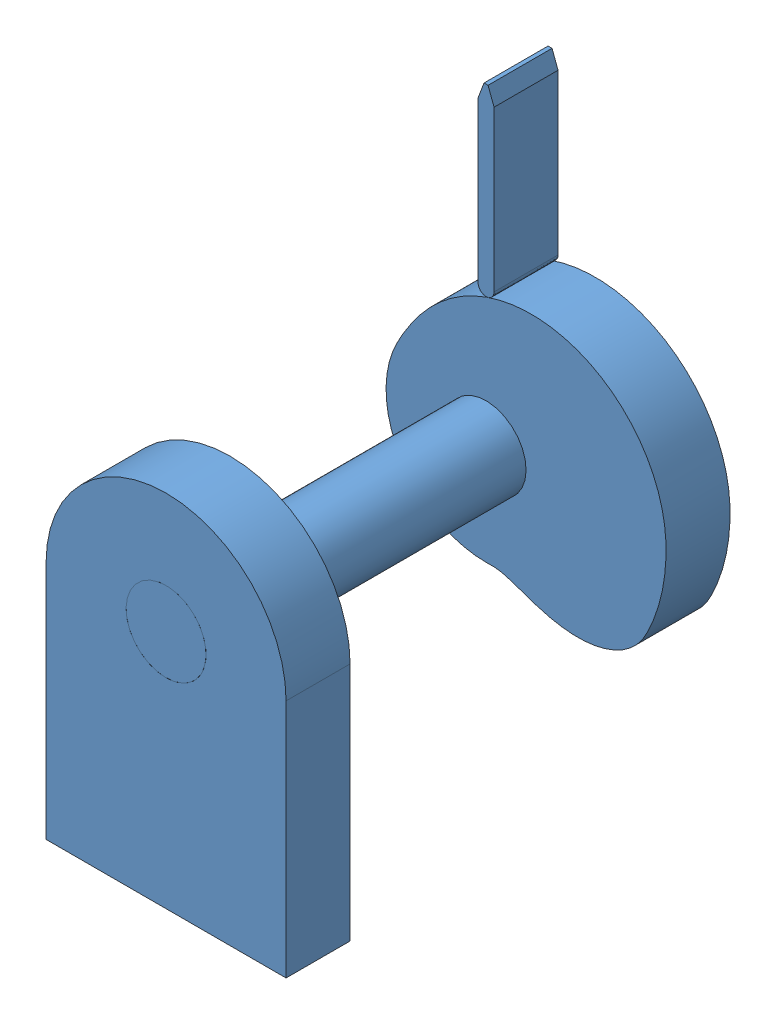
SolidWorks assembly Ensamble_Leva_2, configuration Default. Lengths in mm.
Overall size (515.65 692.74 480).
4 component instances, 1 part files, 7 mates.
Components (placement in the parent):
- Leva_2-1: Leva_2 [Soporte] at (155.9619 263.6656 402.9067) size (375 450 80)
- Leva_2-2: Leva_2 [Eje] at (155.9619 263.6656 42.9067) x (-0.887814 0.460203 0) z (0 0 1) size (350 322.5 480)
- Leva_2-3: Leva_2 [Leva] at (155.9619 263.6656 2.9067) x (-0.887814 0.460203 0) z (0 0 1) size (350 322.5 80)
- Leva_2-5: Leva_2 [Seguidor] at (155.9619 436.4083 -37.0933) size (350 417.5 80)
Mates (geometry in assembly coordinates):
- Concéntrica2: concentric: circle of Leva_2-1; circle of Leva_2-2
- Coincidente5: coincident: plane of Leva_2-1 through (155.9619 263.6656 442.9067) normal (0 0 1); plane of Leva_2-2 through (155.9619 263.6656 442.9067) normal (0 0 1)
- Coincidente11: coincident: circle of Leva_2-2; circle of Leva_2-3
- Coincidente12: coincident: line of Leva_2-2 through (149.0258 195.9608 -37.0933) axis (-0.887814 0.460203 0); line of Leva_2-3 through (104.6351 218.9709 -37.0933) axis (0.887814 -0.460203 0)
- Coincidente27: coincident: plane of Leva_2-1 through (155.9619 263.6656 402.9067) normal (1 0 0); plane of Leva_2-5 through (155.9619 436.4083 -37.0933) normal (1 0 0)
- Coincidente28: coincident: plane of Leva_2-3 through (375.2779 213.4112 -37.0933) normal (0 0 -1); plane of Leva_2-5 through (155.9619 436.4083 -37.0933) normal (0 0 -1)
- Relación de posición de Leva Tangente1: cam tangent: face of Leva_2-3; cylinder of Leva_2-5 through (155.9619 436.4083 42.9067) axis (0 0 -1) radius 10
